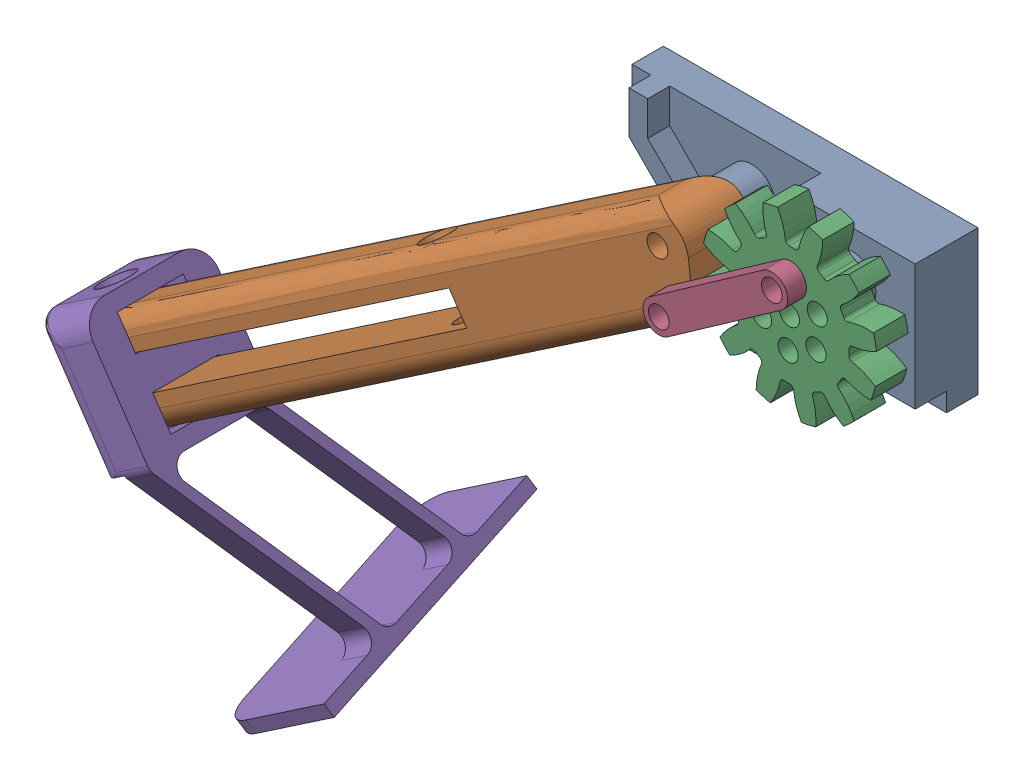
SolidWorks assembly Left Module Assm, configuration Default. Lengths in mm.
Overall size (138.92 121.96 48.17).
5 component instances, 5 part files, 11 mates.
Components (placement in the parent):
- Left Module Mk.2-1: Left Module Mk.2 [Default] at origin size (50.05 30 15)
- Arm Mk.2-1: Arm Mk.2 [geardemo] at (4 15 20) x (-0.827622 -0.561287 0) z (0 0 -1) size (115.1 14.92 10.2)
- Arm Gear Mk.2-1: Arm Gear Mk.2 [geardemo] at (25 16 17.5) x (-0.999133 0.041639 0) z (0 0 1) size (27.56 27.56 5)
- Crank Mk.2-1: Crank Mk.2 [geardemo] at (7.2157 8.3359 20) x (0.81784 0.575446 0) z (0 0 1) size (27 5 3)
- Compliant Foot-1: Compliant Foot [Default] at (-81.5481 -45.9289 15) x (0 0 1) z (-0.827622 -0.561287 0) size (48.17 55.03 20)
Mates (geometry in assembly coordinates):
- Coincident1: coordinate: point of Left Module Mk.2-1
- Coincident2: coincident aligned: line of Left Module Mk.2-1 through (4 15 0) axis (0 0 1); line of Arm Mk.2-1 through (4 15 10) axis (0 0 1)
- Coincident3: coincident anti-aligned: plane of Left Module Mk.2-1 through (4 15 10) normal (0 0 1); plane of Arm Mk.2-1 through (4 15 10) normal (0 0 -1)
- Coincident4: coincident anti-aligned: line of Left Module Mk.2-1 through (25 16 0) axis (0 0 1); line of Arm Gear Mk.2-1 through (25 16 20) axis (0 0 -1)
- Coincident5: coincident anti-aligned: plane of Left Module Mk.2-1 through (25 16 15) normal (0 0 1); plane of Arm Gear Mk.2-1 through (25 16 15) normal (0 0 -1)
- Coincident6: coincident anti-aligned: line of Arm Mk.2-1 through (7.2157 8.3359 10) axis (0 0 1); line of Crank Mk.1-1 through (7.2157 8.3359 23) axis (0 0 -1)
- Coincident7: coincident anti-aligned: plane of Arm Mk.2-1 through (4 15 20) normal (0 0 1); plane of Crank Mk.1-1 through (7.2157 8.3359 20) normal (0 0 -1)
- Coincident8: coincident anti-aligned: line of Arm Gear Mk.2-1 through (25.2082 20.9957 15) axis (0 0 1); line of Crank Mk.1-1 through (25.2082 20.9957 23) axis (0 0 -1)
- Concentric1: concentric anti-aligned: cylinder of Arm Mk.2-1 through (-77.2874 -52.2113 15) axis (-0.561287 0.827622 0) radius 2.5; cylinder of Compliant Foot-1 through (-75.9352 -54.2051 15) axis (0.561287 -0.827622 0) radius 2.75
- Parallel1: parallel anti-aligned: plane of Arm Mk.2-1 through (-31.9113 -3.3134 10) normal (-0.827622 -0.561287 0); plane of Compliant Foot-1 through (-77.41 -43.1225 15) normal (0.827622 0.561287 0)
- Width1: width anti-aligned: plane of Compliant Foot-1 through (-87.0333 -46.749 15) normal (-0.561287 0.827622 0); plane of Arm Mk.2-1 through (-84.3391 -50.7216 15) normal (0.561287 -0.827622 0); plane of Compliant Foot-1 through (-87.0894 -46.6663 10) normal (0.561287 -0.827622 0); plane of Arm Mk.2-1 through (-84.283 -50.8044 10) normal (-0.561287 0.827622 0)
